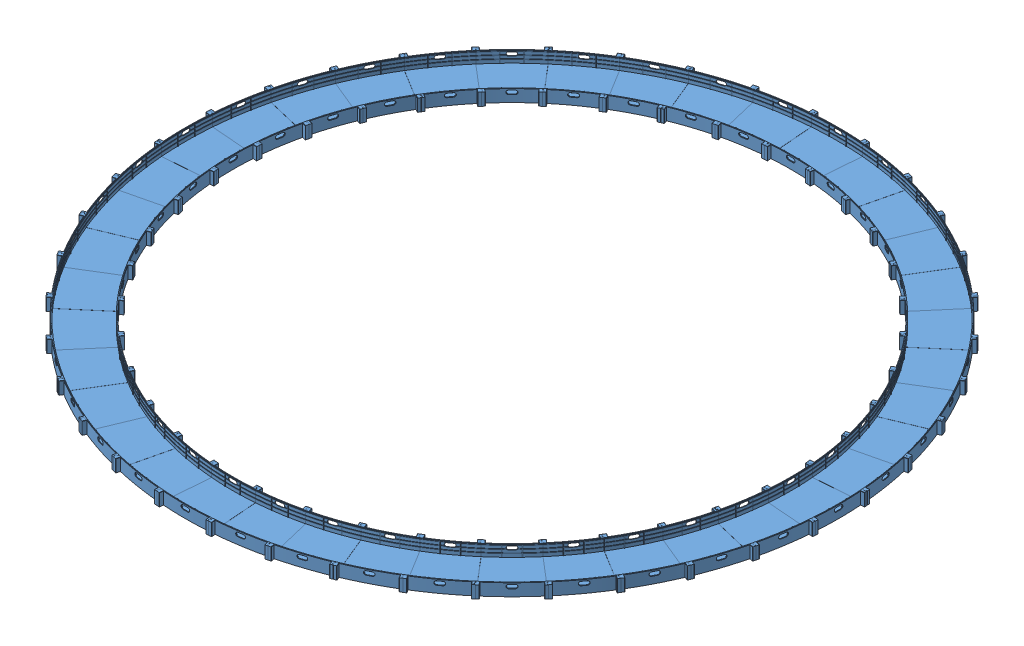
SolidWorks assembly Assem1, configuration Default. Lengths in mm.
Overall size (2814.96 55 2814.96).
40 component instances, 1 part files, 3 mates.
Components (placement in the parent):
- new_terrain_piece-1: new_terrain_piece [Default] at (14.1007 92.8658 1501.8426) size (224.43 55 221.7)
- new_terrain_piece-2: new_terrain_piece [Default] at (13.9013 92.8658 1501.8269) x (0.987688 0 0.156434) z (-0.156434 0 0.987688) size (224.43 55 221.7)
- new_terrain_piece-3: new_terrain_piece [Default] at (13.9159 92.8658 1501.7661) x (0.891007 0 0.45399) z (-0.45399 0 0.891007) size (224.43 55 221.7)
- new_terrain_piece-4: new_terrain_piece [Default] at (13.9486 92.8658 1501.7127) x (0.707107 0 0.707107) z (-0.707107 0 0.707107) size (224.43 55 221.7)
- new_terrain_piece-5: new_terrain_piece [Default] at (13.9962 92.8658 1501.6721) x (0.45399 0 0.891007) z (-0.891007 0 0.45399) size (224.43 55 221.7)
- new_terrain_piece-6: new_terrain_piece [Default] at (14.054 92.8658 1501.6481) x (0.156434 0 0.987688) z (-0.987688 0 0.156434) size (224.43 55 221.7)
- new_terrain_piece-7: new_terrain_piece [Default] at (14.1164 92.8658 1501.6432) x (-0.156434 0 0.987688) z (-0.987688 0 -0.156434) size (224.43 55 221.7)
- new_terrain_piece-8: new_terrain_piece [Default] at (14.1772 92.8658 1501.6578) x (-0.45399 0 0.891007) z (-0.891007 0 -0.45399) size (224.43 55 221.7)
- new_terrain_piece-9: new_terrain_piece [Default] at (14.2306 92.8658 1501.6905) x (-0.707107 0 0.707107) z (-0.707107 0 -0.707107) size (224.43 55 221.7)
- new_terrain_piece-10: new_terrain_piece [Default] at (14.2712 92.8658 1501.7381) x (-0.891007 0 0.45399) z (-0.45399 0 -0.891007) size (224.43 55 221.7)
- new_terrain_piece-11: new_terrain_piece [Default] at (14.2952 92.8658 1501.7959) x (-0.987688 0 0.156434) z (-0.156434 0 -0.987688) size (224.43 55 221.7)
- new_terrain_piece-12: new_terrain_piece [Default] at (14.3001 92.8658 1501.8583) x (-0.987688 0 -0.156434) z (0.156434 0 -0.987688) size (224.43 55 221.7)
- new_terrain_piece-13: new_terrain_piece [Default] at (14.2855 92.8658 1501.9192) x (-0.891007 0 -0.45399) z (0.45399 0 -0.891007) size (224.43 55 221.7)
- new_terrain_piece-14: new_terrain_piece [Default] at (14.2528 92.8658 1501.9725) x (-0.707107 0 -0.707107) z (0.707107 0 -0.707107) size (224.43 55 221.7)
- new_terrain_piece-15: new_terrain_piece [Default] at (14.2052 92.8658 1502.0132) x (-0.45399 0 -0.891007) z (0.891007 0 -0.45399) size (224.43 55 221.7)
- new_terrain_piece-16: new_terrain_piece [Default] at (14.1474 92.8658 1502.0371) x (-0.156434 0 -0.987688) z (0.987688 0 -0.156434) size (224.43 55 221.7)
- new_terrain_piece-17: new_terrain_piece [Default] at (14.085 92.8658 1502.042) x (0.156434 0 -0.987688) z (0.987688 0 0.156434) size (224.43 55 221.7)
- new_terrain_piece-18: new_terrain_piece [Default] at (14.0242 92.8658 1502.0274) x (0.45399 0 -0.891007) z (0.891007 0 0.45399) size (224.43 55 221.7)
- new_terrain_piece-19: new_terrain_piece [Default] at (13.9708 92.8658 1501.9947) x (0.707107 0 -0.707107) z (0.707107 0 0.707107) size (224.43 55 221.7)
- new_terrain_piece-20: new_terrain_piece [Default] at (13.9302 92.8658 1501.9471) x (0.891007 0 -0.45399) z (0.45399 0 0.891007) size (224.43 55 221.7)
- new_terrain_piece-21: new_terrain_piece [Default] at (13.9062 92.8658 1501.8893) x (0.987688 0 -0.156434) z (0.156434 0 0.987688) size (224.43 55 221.7)
- new_terrain_piece-22: new_terrain_piece [Default] at (14.1007 92.8658 1501.8426) x (0.951057 0 0.309017) z (-0.309017 0 0.951057) size (224.43 55 221.7)
- new_terrain_piece-23: new_terrain_piece [Default] at (14.1007 92.8658 1501.8426) x (0.809017 0 0.587785) z (-0.587785 0 0.809017) size (224.43 55 221.7)
- new_terrain_piece-24: new_terrain_piece [Default] at (14.1007 92.8658 1501.8426) x (0.587785 0 0.809017) z (-0.809017 0 0.587785) size (224.43 55 221.7)
- new_terrain_piece-25: new_terrain_piece [Default] at (14.1007 92.8658 1501.8426) x (0.309017 0 0.951057) z (-0.951057 0 0.309017) size (224.43 55 221.7)
- new_terrain_piece-26: new_terrain_piece [Default] at (14.1007 92.8658 1501.8426) x (0 0 1) z (-1 0 0) size (224.43 55 221.7)
- new_terrain_piece-27: new_terrain_piece [Default] at (14.1007 92.8658 1501.8426) x (-0.309017 0 0.951057) z (-0.951057 0 -0.309017) size (224.43 55 221.7)
- new_terrain_piece-28: new_terrain_piece [Default] at (14.1007 92.8658 1501.8426) x (-0.587785 0 0.809017) z (-0.809017 0 -0.587785) size (224.43 55 221.7)
- new_terrain_piece-29: new_terrain_piece [Default] at (14.1007 92.8658 1501.8426) x (-0.809017 0 0.587785) z (-0.587785 0 -0.809017) size (224.43 55 221.7)
- new_terrain_piece-30: new_terrain_piece [Default] at (14.1007 92.8658 1501.8426) x (-0.951057 0 0.309017) z (-0.309017 0 -0.951057) size (224.43 55 221.7)
- new_terrain_piece-31: new_terrain_piece [Default] at (14.1007 92.8658 1501.8426) x (-1 0 0) z (0 0 -1) size (224.43 55 221.7)
- new_terrain_piece-32: new_terrain_piece [Default] at (14.1007 92.8658 1501.8426) x (-0.951057 0 -0.309017) z (0.309017 0 -0.951057) size (224.43 55 221.7)
- new_terrain_piece-33: new_terrain_piece [Default] at (14.1007 92.8658 1501.8426) x (-0.809017 0 -0.587785) z (0.587785 0 -0.809017) size (224.43 55 221.7)
- new_terrain_piece-34: new_terrain_piece [Default] at (14.1007 92.8658 1501.8426) x (-0.587785 0 -0.809017) z (0.809017 0 -0.587785) size (224.43 55 221.7)
- new_terrain_piece-35: new_terrain_piece [Default] at (14.1007 92.8658 1501.8426) x (-0.309017 0 -0.951057) z (0.951057 0 -0.309017) size (224.43 55 221.7)
- new_terrain_piece-36: new_terrain_piece [Default] at (14.1007 92.8658 1501.8426) x (0 0 -1) z (1 0 0) size (224.43 55 221.7)
- new_terrain_piece-37: new_terrain_piece [Default] at (14.1007 92.8658 1501.8426) x (0.309017 0 -0.951057) z (0.951057 0 0.309017) size (224.43 55 221.7)
- new_terrain_piece-38: new_terrain_piece [Default] at (14.1007 92.8658 1501.8426) x (0.587785 0 -0.809017) z (0.809017 0 0.587785) size (224.43 55 221.7)
- new_terrain_piece-39: new_terrain_piece [Default] at (14.1007 92.8658 1501.8426) x (0.809017 0 -0.587785) z (0.587785 0 0.809017) size (224.43 55 221.7)
- new_terrain_piece-40: new_terrain_piece [Default] at (14.1007 92.8658 1501.8426) x (0.951057 0 -0.309017) z (0.309017 0 0.951057) size (224.43 55 221.7)
Mates (geometry in assembly coordinates):
- Coincident2: coincident anti-aligned: plane of new_terrain_piece-1 through (17.9887 169.8165 1502.1486) normal (0.996917 0 0.078459); plane of new_terrain_piece-2 through (17.9887 169.8165 1502.1486) normal (-0.996917 0 -0.078459)
- Coincident3: coincident aligned: plane of new_terrain_piece-1 through (14.1007 145.8658 1501.8426) normal (0 1 0); plane of new_terrain_piece-2 through (13.9013 145.8658 1501.8269) normal (0 1 0)
- Distance1: distance = 0.3 mm anti-aligned: plane of new_terrain_piece-1 through (-513.3004 169.8165 396.1233) normal (-0.430511 0 -0.902585); plane of new_terrain_piece-2 through (-513.5858 169.8165 395.9271) normal (0.430511 0 0.902585)
